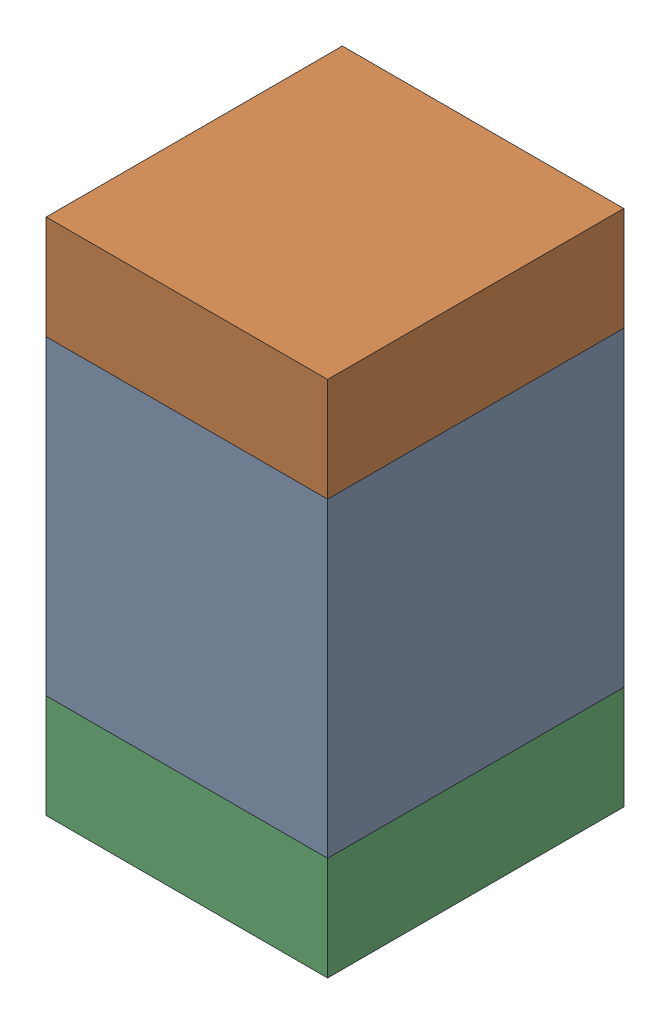
SolidWorks assembly C319_1PCB, configuration Default. Lengths in mm.
Overall size (0.95 1.75 1).
6 component instances, 2 part files, 0 mates.
Components (placement in the parent):
- 761616384-1: 761616384 [Default] at (126.6343 109.85 0) size (0.95 1.05 1)
  - Extruded_5-1: Extruded_5 [Default] at origin size (0.95 1.05 1)
- 761616520-1: 761616520 [Default] at (126.6343 110.55 0) size (0.95 0.35 1)
  - Extruded_6-1: Extruded_6 [Default] at origin size (0.95 0.35 1)
- 761616520-2: 761616520 [Default] at (126.6343 109.15 0) size (0.95 0.35 1)
  - Extruded_6-1: Extruded_6 [Default] at origin size (0.95 0.35 1)
